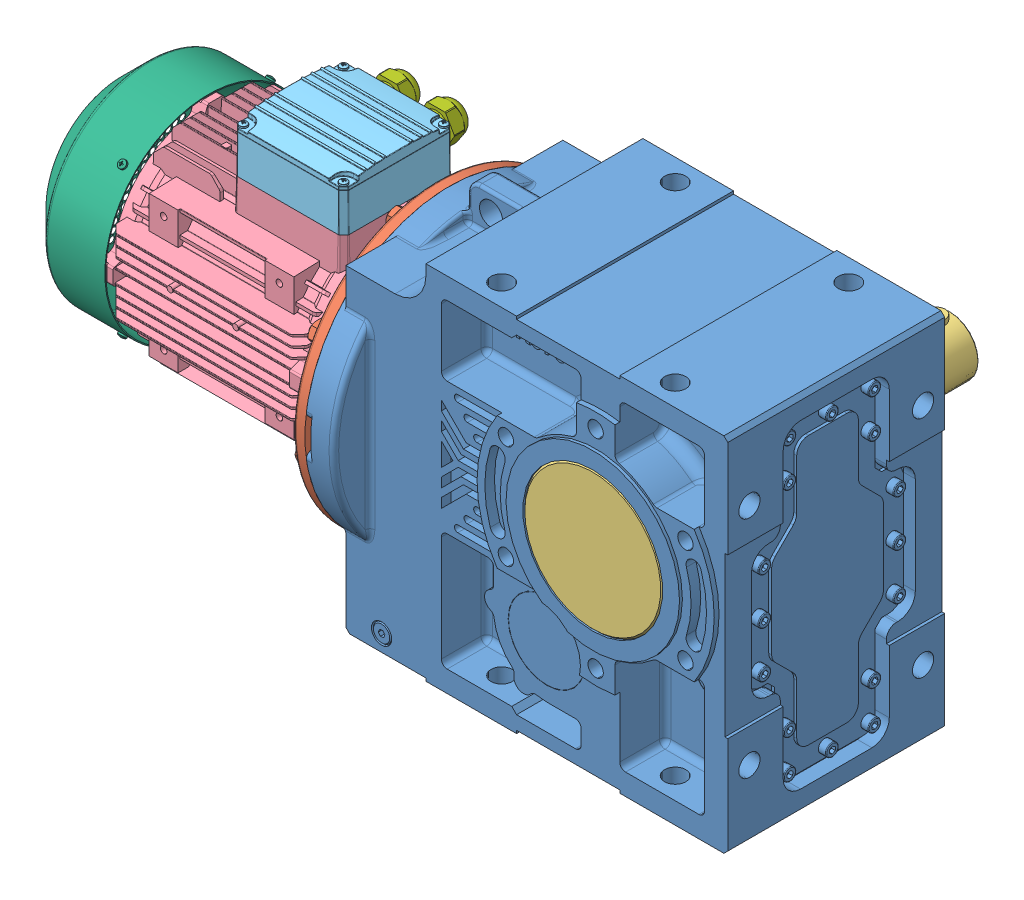
SolidWorks assembly SHRPRO-V1 4kW Motor KR573 L3E112M, configuration Predeterminado. Lengths in mm.
Overall size (742.62 375.04 414.79).
7 component instances, 7 part files, 0 mates.
Components (placement in the parent):
- K573_Varsay_lan(2)-1: K573_Varsay_lan(2) [Predeterminado] at (-931.5001 -975.5016 -1000) size (401 375.04 329.58)
- 533E112_Varsay_lan-1: 533E112_Varsay_lan [Predeterminado] at (-1246.5001 -993.0016 -1000) x (0 0 -1) z (1 0 0) size (300 300 46)
- ML5A_L_Varsay_lan(2)-1: ML5A_L_Varsay_lan(2) [Predeterminado] at (-931.5001 -975.5016 -877) x (0 0 1) z (-1 0 0) size (370.5 145 145)
- 3E112M_DA_Varsay_lan-1: 3E112M_DA_Varsay_lan [Predeterminado] at (-1351.5001 -993.0016 -1000) x (0 0 -1) z (1 0 0) size (213 213 210)
- KL_3E112_Varsay_lan-1: KL_3E112_Varsay_lan [Predeterminado] at (-1310.3501 -886.5016 -1000) x (0 0 -1) z (1 0 0) size (116.45 51.17 115.89)
- T_3E112_1_Varsay_lan-1: T_3E112_1_Varsay_lan [Predeterminado] at (-1450.5001 -993.0016 -1000) x (1 0 0) z (0 -0.707107 0.707107) size (91.62 221.05 221.05)
- RK_3E112_Varsay_lan-1: RK_3E112_Varsay_lan [Predeterminado] at (-1285.3501 -866.5016 -1093.5) size (87.5 33.01 45)
